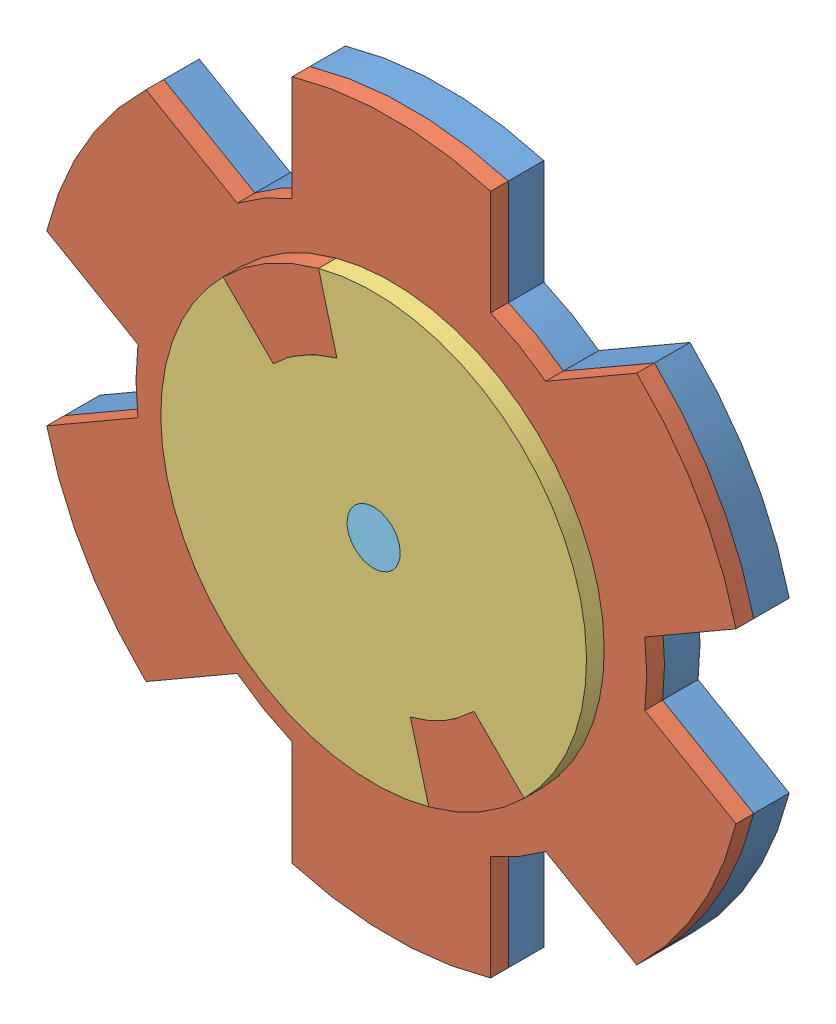
SolidWorks assembly SLATE_mounts, configuration Default. Lengths in mm.
Overall size (61.68 63.5 6.35).
11 component instances, 5 part files, 12 mates.
Components (placement in the parent):
- magnetic_mount_back-1: magnetic_mount_back [Default] at (-17.9312 24.9224 -9.0574) size (61.68 63.5 3.17)
- magnetic_mount_front-1: magnetic_mount_front [Default] at (-17.9312 24.9224 -5.8824) size (61.68 63.5 3.17)
- connector-1: connector [Default] at (-17.9312 24.9224 -2.7074) x (-0.5 -0.866025 0) z (0 0 -1) size (38.1 38.1 1.59)
- n72_magnet-1: n72_magnet [Default] at (2.6713 36.8173 -9.0574) size (11.11 11.11 3.17)
- n72_magnet-2: n72_magnet [Default] at (-17.9312 48.7122 -9.0574) x (0.5 0.866025 0) z (0 0 1) size (11.11 11.11 3.17)
- n72_magnet-3: n72_magnet [Default] at (-38.5337 36.8173 -9.0574) x (-0.5 0.866025 0) z (0 0 1) size (11.11 11.11 3.17)
- n72_magnet-4: n72_magnet [Default] at (-38.5337 13.0276 -9.0574) x (-1 0 0) z (0 0 1) size (11.11 11.11 3.17)
- n72_magnet-5: n72_magnet [Default] at (-17.9312 1.1327 -9.0574) x (-0.5 -0.866025 0) z (0 0 1) size (11.11 11.11 3.17)
- n72_magnet-6: n72_magnet [Default] at (2.6713 13.0276 -9.0574) x (0.5 -0.866025 0) z (0 0 1) size (11.11 11.11 3.17)
- d31_magnet-1: d31_magnet [Default] at (-17.9312 24.9224 -4.2949) x (-0.923728 -0.383049 0) z (0 0 -1) size (4.76 4.76 1.59)
- d31_magnet-2: d31_magnet [Default] at (-17.9312 24.9224 -2.7074) x (-0.923728 -0.383049 0) z (0 0 -1) size (4.76 4.76 1.59)
Mates (geometry in assembly coordinates):
- Coincident1: coincident anti-aligned: plane of magnetic_mount_back-1 through (-17.9312 24.9224 -5.8824) normal (0 0 1); plane of magnetic_mount_front-1 through (-17.9312 24.9224 -5.8824) normal (0 0 -1)
- Coincident2: coincident aligned: plane of magnetic_mount_back-1 through (-9.0524 55.4057 -5.8824) normal (1 0 0); plane of magnetic_mount_front-1 through (-9.0524 45.9842 -4.2949) normal (1 0 0)
- Concentric1: concentric aligned: cylinder of magnetic_mount_back-1 through (-17.9312 24.9224 -5.8824) axis (0 0 -1) radius 31.75; cylinder of magnetic_mount_front-1 through (-17.9312 24.9224 -4.2949) axis (0 0 -1) radius 31.75
- Concentric2: concentric anti-aligned: cylinder of magnetic_mount_front-1 through (-17.9312 24.9224 -5.8824) axis (0 0 1) radius 2.3813; cylinder of connector-1 through (-17.9312 24.9224 -1.1199) axis (0 0 -1) radius 2.3813
- Concentric3: concentric aligned: circle of magnetic_mount_back-1; circle of n72_magnet-1
- Coincident12: coincident anti-aligned: plane of magnetic_mount_front-1 through (-17.9312 24.9224 -5.8824) normal (0 0 -1); plane of n72_magnet-1 through (2.6713 36.8173 -5.8824) normal (0 0 1)
- Coincident13: coincident anti-aligned: plane of magnetic_mount_front-1 through (-22.8617 43.3233 -2.7074) normal (0.965926 0.258819 0); plane of connector-1 through (-10.2352 -3.7992 -2.7074) normal (-0.965926 -0.258819 0)
- Coincident14: coincident anti-aligned: plane of magnetic_mount_front-1 through (-17.9312 24.9224 -4.2949) normal (0 0 1); plane of connector-1 through (-17.9312 24.9224 -4.2949) normal (0 0 -1)
- Coincident15: coincident anti-aligned: plane of magnetic_mount_back-1 through (-17.9312 24.9224 -5.8824) normal (0 0 1); plane of d31_magnet-1 through (-17.9312 24.9224 -5.8824) normal (0 0 -1)
- Coincident16: coincident anti-aligned: circle of magnetic_mount_front-1; circle of d31_magnet-1
- Coincident17: coincident anti-aligned: plane of d31_magnet-1 through (-17.9312 24.9224 -4.2949) normal (0 0 1); plane of d31_magnet-2 through (-17.9312 24.9224 -4.2949) normal (0 0 -1)
- Concentric4: concentric anti-aligned: cylinder of connector-1 through (-17.9312 24.9224 -1.1199) axis (0 0 -1) radius 2.3813; cylinder of d31_magnet-2 through (-17.9312 24.9224 -4.2949) axis (0 0 1) radius 2.3813
